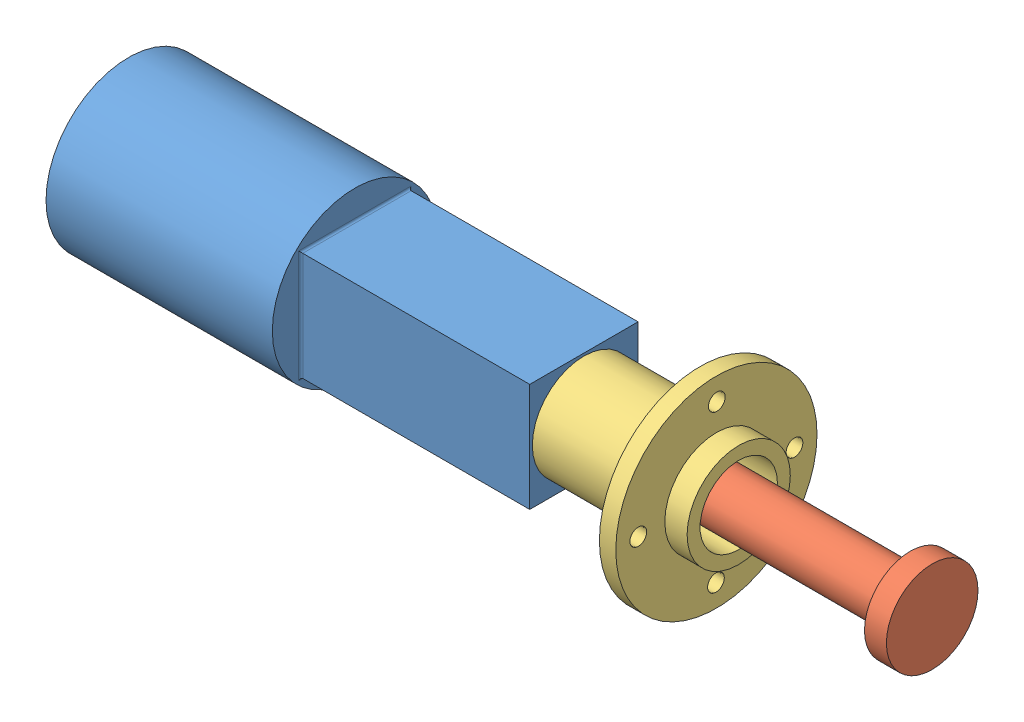
SolidWorks assembly D-01-04, configuration Default. Lengths in mm.
Overall size (311.5 78.45 78.45).
3 component instances, 3 part files, 0 mates.
Components (placement in the parent):
- moteur_pla_simplifie-2: moteur_pla_simplifie [Default] at (-156.9384 51.1827 137.4238) size (176.5 64 64)
- moteur_axe_pla_simplifie-1: moteur_axe_pla_simplifie [Default] at (3.5616 51.1827 137.4238) size (151 35.5 35.5)
- front_housing_moteur_pla_simplifie-2: front_housing_moteur_pla_simplifie [Default] at (64.5616 51.1827 137.4238) x (1 0 0) z (0 0.00581 0.999983) size (60 78 78)
